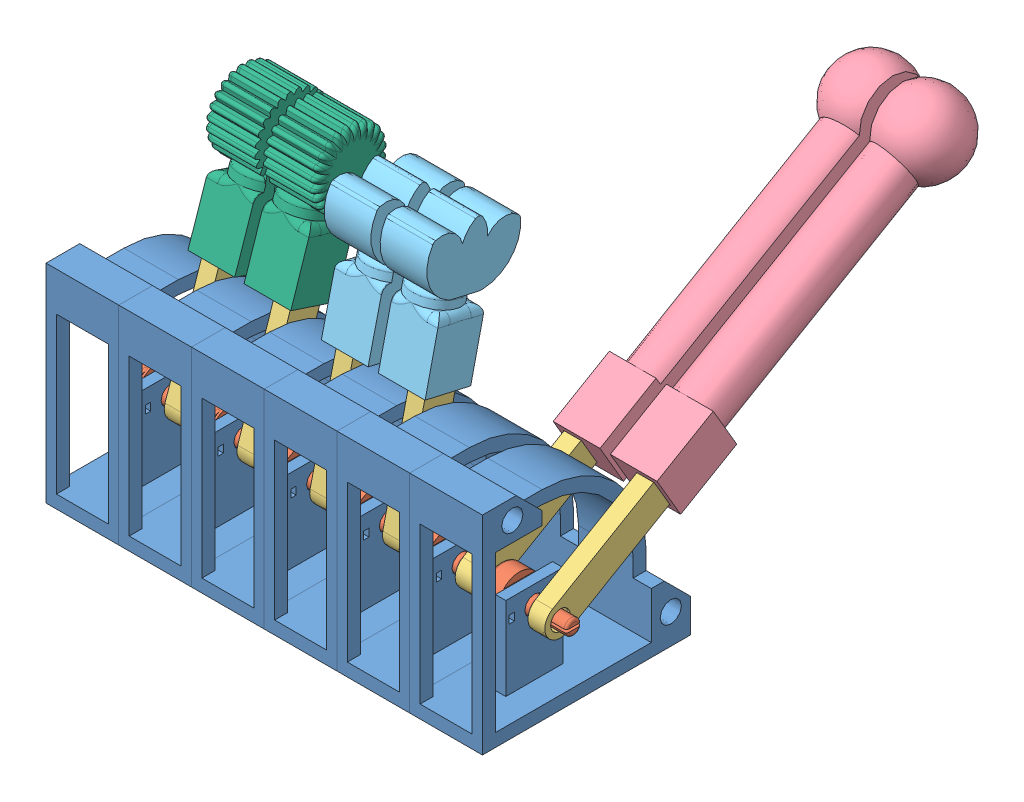
SolidWorks assembly throttle_quadrant_module_v2, configuration По умолчанию. Lengths in mm.
Overall size (176 136.41 197.26).
24 component instances, 6 part files, 57 mates.
Components (placement in the parent):
- throttle_quadrant_axis_module_throttle_quadrant01a-1: throttle_quadrant_axis_module_throttle_quadrant01a [По умолчанию] at origin size (28 80 80)
- 16K1-B10K-1: 16K1-B10K [По умолчанию] at (5.1 0 0) x (0 -1 0) z (0 0 1) size (20 28.16 16.3)
- throttle_quadrant_axis_module_slider_throttle_quadrant02a-1: throttle_quadrant_axis_module_slider_throttle_quadrant02a [По умолчанию] at (28 0 0) x (0 0.222506 0.974931) z (0 -0.974931 0.222506) size (12 6.5 71)
- throttle_quadrant_axis_module_throttle_quadrant01a-2: throttle_quadrant_axis_module_throttle_quadrant01a [По умолчанию] at (28 0 0) size (28 80 80)
- 16K1-B10K-2: 16K1-B10K [По умолчанию] at (33.1 0 0) x (0 -1 0) z (0 0 1) size (20 28.16 16.3)
- throttle_quadrant_axis_module_throttle_quadrant01a-4: throttle_quadrant_axis_module_throttle_quadrant01a [По умолчанию] at (56 0 0) size (28 80 80)
- throttle_quadrant_axis_module_slider_throttle_quadrant02a-2: throttle_quadrant_axis_module_slider_throttle_quadrant02a [По умолчанию] at (56 0 0) x (0 0.863825 0.503792) z (0 -0.503792 0.863825) size (12 6.5 71)
- throttle_quadrant_axis_module_slider_throttle_quadrant02a-3: throttle_quadrant_axis_module_slider_throttle_quadrant02a [По умолчанию] at (84 0 0) x (0 0.863572 0.504225) z (0 -0.504225 0.863572) size (12 6.5 71)
- 16K1-B10K-3: 16K1-B10K [По умолчанию] at (61.1 0 0) x (0 -1 0) z (0 0 1) size (20 28.16 16.3)
- mi8_throttle-1: mi8_throttle [По умолчанию] at (69 29.1657 -49.5546) x (1 0 0) z (0 0.863572 0.504225) size (23.51 140 30)
- mi8_throttle-2: mi8_throttle [По умолчанию] at (65 29.1408 -49.5692) x (-1 0 0) z (0 -0.863825 -0.503792) size (23.51 140 30)
- throttle_quadrant_axis_module_throttle_quadrant01a-5: throttle_quadrant_axis_module_throttle_quadrant01a [По умолчанию] at (-28 0 0) size (28 80 80)
- 16K1-B10K-4: 16K1-B10K [По умолчанию] at (-22.9 0 0) x (0 -1 0) z (0 0 1) size (20 28.16 16.3)
- throttle_quadrant_axis_module_slider_throttle_quadrant02a-4: throttle_quadrant_axis_module_slider_throttle_quadrant02a [По умолчанию] x (0 0.23184 0.972754) z (0 -0.972754 0.23184) size (12 6.5 71)
- prop_knob-1: prop_knob [По умолчанию] at (8.5 55.9797 -13.1363) x (-1 0 0) z (0 -0.23184 -0.972754) size (18 54.43 36.33)
- prop_knob-2: prop_knob [По умолчанию] at (12.5 56.0141 -12.9891) x (1 0 0) z (0 0.222506 0.974931) size (18 54.43 36.33)
- throttle_quadrant_axis_module_throttle_quadrant01a-6: throttle_quadrant_axis_module_throttle_quadrant01a [По умолчанию] at (-84 0 0) size (28 80 80)
- throttle_quadrant_axis_module_throttle_quadrant01a-7: throttle_quadrant_axis_module_throttle_quadrant01a [По умолчанию] at (-56 0 0) size (28 80 80)
- 16K1-B10K-5: 16K1-B10K [По умолчанию] at (-78.9 0 0) x (0 -0.381849 0.924225) z (0 0.924225 0.381849) size (20 28.16 16.3)
- 16K1-B10K-6: 16K1-B10K [По умолчанию] at (-50.9 0 0) x (0 -0.381849 0.924225) z (0 0.924225 0.381849) size (20 28.16 16.3)
- throttle_quadrant_axis_module_slider_throttle_quadrant02a-5: throttle_quadrant_axis_module_slider_throttle_quadrant02a [По умолчанию] at (-56 0 0) x (0 0.3217 0.946842) z (0 -0.946842 0.3217) size (12 6.5 71)
- throttle_quadrant_axis_module_slider_throttle_quadrant02a-6: throttle_quadrant_axis_module_slider_throttle_quadrant02a [По умолчанию] at (-28 0 0) x (0 0.31364 0.949542) z (0 -0.949542 0.31364) size (12 6.5 71)
- mix_knob-1: mix_knob [По умолчанию] at (-47.5 54.3791 -18.6871) x (-1 0 0) z (0 -0.3217 -0.946842) size (20 56.24 28.48)
- mix_knob-2: mix_knob [По умолчанию] at (-43.5 54.5359 -18.2242) x (1 0 0) z (0 0.31364 0.949542) size (20 56.24 28.48)
Mates (geometry in assembly coordinates):
- Concentric1: concentric anti-aligned: cylinder of throttle_quadrant_axis_module_throttle_quadrant01a-1 through (14 0 0) axis (1 0 0) radius 3.7; cylinder of 16K1-B10K-1 through (20.4 0 0) axis (-1 0 0) radius 3.35
- Coincident1: coincident anti-aligned: plane of throttle_quadrant_axis_module_throttle_quadrant01a-1 through (14 0 0) normal (-1 0 0); plane of 16K1-B10K-1 through (14 0 0) normal (1 0 0)
- Concentric2: concentric anti-aligned: cylinder of 16K1-B10K-1 through (33.2 0 0) axis (-1 0 0) radius 2.9; cylinder of throttle_quadrant_axis_module_slider_throttle_quadrant02a-1 through (21.5 0 0) axis (1 0 0) radius 3.75
- Distance2: distance = 0.5 mm anti-aligned: plane of throttle_quadrant_axis_module_slider_throttle_quadrant02a-1 through (21.5 0 0) normal (-1 0 0); plane of throttle_quadrant_axis_module_throttle_quadrant01a-1 through (21 0 0) normal (1 0 0)
- Concentric3: concentric aligned: cylinder of throttle_quadrant_axis_module_throttle_quadrant01a-1 through (0 42.5 18.5) axis (1 0 0) radius 4.1; cylinder of throttle_quadrant_axis_module_throttle_quadrant01a-2 through (28 42.5 18.5) axis (1 0 0) radius 4.1
- Concentric4: concentric aligned: cylinder of throttle_quadrant_axis_module_throttle_quadrant01a-1 through (0 -18.5 -42.5) axis (1 0 0) radius 4.1; cylinder of throttle_quadrant_axis_module_throttle_quadrant01a-2 through (28 -18.5 -42.5) axis (1 0 0) radius 4.1
- Coincident5: coincident anti-aligned: plane of throttle_quadrant_axis_module_throttle_quadrant01a-1 through (28 0 0) normal (1 0 0); plane of throttle_quadrant_axis_module_throttle_quadrant01a-2 through (28 0 0) normal (-1 0 0)
- Concentric5: concentric anti-aligned: cylinder of throttle_quadrant_axis_module_throttle_quadrant01a-2 through (42 0 0) axis (1 0 0) radius 3.7; cylinder of 16K1-B10K-2 through (48.4 0 0) axis (-1 0 0) radius 3.35
- Coincident6: coincident anti-aligned: plane of throttle_quadrant_axis_module_throttle_quadrant01a-2 through (42 0 0) normal (-1 0 0); plane of 16K1-B10K-2 through (42 0 0) normal (1 0 0)
- Concentric8: concentric aligned: cylinder of throttle_quadrant_axis_module_throttle_quadrant01a-2 through (28 42.5 18.5) axis (1 0 0) radius 4.1; cylinder of throttle_quadrant_axis_module_throttle_quadrant01a-4 through (56 42.5 18.5) axis (1 0 0) radius 4.1
- Concentric9: concentric aligned: cylinder of throttle_quadrant_axis_module_throttle_quadrant01a-2 through (28 -18.5 -42.5) axis (1 0 0) radius 4.1; cylinder of throttle_quadrant_axis_module_throttle_quadrant01a-4 through (56 -18.5 -42.5) axis (1 0 0) radius 4.1
- Coincident8: coincident anti-aligned: plane of throttle_quadrant_axis_module_throttle_quadrant01a-2 through (56 0 0) normal (1 0 0); plane of throttle_quadrant_axis_module_throttle_quadrant01a-4 through (56 0 0) normal (-1 0 0)
- Concentric10: concentric anti-aligned: cylinder of 16K1-B10K-2 through (61.2 0 0) axis (-1 0 0) radius 2.9; cylinder of throttle_quadrant_axis_module_slider_throttle_quadrant02a-2 through (49.5 0 0) axis (1 0 0) radius 3.75
- Concentric11: concentric anti-aligned: cylinder of throttle_quadrant_axis_module_throttle_quadrant01a-4 through (70 0 0) axis (1 0 0) radius 3.7; cylinder of 16K1-B10K-3 through (76.4 0 0) axis (-1 0 0) radius 3.35
- Coincident10: coincident anti-aligned: plane of throttle_quadrant_axis_module_throttle_quadrant01a-4 through (70 0 0) normal (-1 0 0); plane of 16K1-B10K-3 through (70 0 0) normal (1 0 0)
- Concentric12: concentric anti-aligned: cylinder of throttle_quadrant_axis_module_slider_throttle_quadrant02a-3 through (77.5 0 0) axis (1 0 0) radius 3.75; cylinder of 16K1-B10K-3 through (89.2 0 0) axis (-1 0 0) radius 2.9
- Distance4: distance = 0.5 mm anti-aligned: plane of throttle_quadrant_axis_module_slider_throttle_quadrant02a-2 through (49.5 0 0) normal (-1 0 0); plane of throttle_quadrant_axis_module_throttle_quadrant01a-2 through (49 0 0) normal (1 0 0)
- Distance5: distance = 0.5 mm anti-aligned: plane of throttle_quadrant_axis_module_slider_throttle_quadrant02a-3 through (77.5 0 0) normal (-1 0 0); plane of throttle_quadrant_axis_module_throttle_quadrant01a-4 through (77 0 0) normal (1 0 0)
- Coincident13: coincident anti-aligned: plane of throttle_quadrant_axis_module_slider_throttle_quadrant02a-3 through (77.5 0 0) normal (-1 0 0); plane of mi8_throttle-1 through (77.5 27.5932 -59.1575) normal (1 0 0)
- Coincident14: coincident anti-aligned: plane of throttle_quadrant_axis_module_slider_throttle_quadrant02a-3 through (77.5 27.5932 -59.1575) normal (0 0.504225 -0.863572); plane of mi8_throttle-1 through (69 32.9474 -56.0313) normal (0 -0.504225 0.863572)
- Coincident15: coincident anti-aligned: plane of throttle_quadrant_axis_module_slider_throttle_quadrant02a-3 through (77.5 -5.1814 -3.0254) normal (0 -0.863572 -0.504225); plane of mi8_throttle-1 through (77.5 27.5932 -59.1575) normal (0 0.863572 0.504225)
- Coincident16: coincident anti-aligned: plane of throttle_quadrant_axis_module_slider_throttle_quadrant02a-2 through (49.5 0 0) normal (-1 0 0); plane of mi8_throttle-2 through (49.5 38.275 -52.9243) normal (1 0 0)
- Coincident17: coincident anti-aligned: plane of throttle_quadrant_axis_module_slider_throttle_quadrant02a-2 through (49.5 27.5636 -59.1714) normal (0 0.503792 -0.863825); plane of mi8_throttle-2 through (65 32.9193 -56.0479) normal (0 -0.503792 0.863825)
- Coincident18: coincident anti-aligned: plane of throttle_quadrant_axis_module_slider_throttle_quadrant02a-2 through (49.5 -5.1829 -3.0228) normal (0 -0.863825 -0.503792); plane of mi8_throttle-2 through (56.5 27.5636 -59.1714) normal (0 0.863825 0.503792)
- Concentric14: concentric aligned: cylinder of throttle_quadrant_axis_module_throttle_quadrant01a-1 through (0 42.5 18.5) axis (1 0 0) radius 4.1; cylinder of throttle_quadrant_axis_module_throttle_quadrant01a-5 through (-28 42.5 18.5) axis (1 0 0) radius 4.1
- Concentric15: concentric aligned: cylinder of throttle_quadrant_axis_module_throttle_quadrant01a-1 through (0 -18.5 -42.5) axis (1 0 0) radius 4.1; cylinder of throttle_quadrant_axis_module_throttle_quadrant01a-5 through (-28 -18.5 -42.5) axis (1 0 0) radius 4.1
- Coincident19: coincident anti-aligned: plane of throttle_quadrant_axis_module_throttle_quadrant01a-1 through (0 0 0) normal (-1 0 0); plane of throttle_quadrant_axis_module_throttle_quadrant01a-5 through (0 0 0) normal (1 0 0)
- Concentric16: concentric anti-aligned: cylinder of throttle_quadrant_axis_module_throttle_quadrant01a-5 through (-14 0 0) axis (1 0 0) radius 3.7; cylinder of 16K1-B10K-4 through (-7.6 0 0) axis (-1 0 0) radius 3.35
- Coincident20: coincident anti-aligned: plane of throttle_quadrant_axis_module_throttle_quadrant01a-5 through (-14 0 0) normal (-1 0 0); plane of 16K1-B10K-4 through (-14 0 0) normal (1 0 0)
- Concentric17: concentric anti-aligned: cylinder of 16K1-B10K-4 through (5.2 0 0) axis (-1 0 0) radius 2.9; cylinder of throttle_quadrant_axis_module_slider_throttle_quadrant02a-4 through (-6.5 0 0) axis (1 0 0) radius 3.75
- Distance6: distance = 0.5 mm anti-aligned: plane of throttle_quadrant_axis_module_slider_throttle_quadrant02a-4 through (-6.5 0 0) normal (-1 0 0); plane of throttle_quadrant_axis_module_throttle_quadrant01a-5 through (-7 0 0) normal (1 0 0)
- Coincident22: coincident anti-aligned: plane of throttle_quadrant_axis_module_slider_throttle_quadrant02a-1; plane of prop_knob-2
- Coincident23: coincident anti-aligned: plane of throttle_quadrant_axis_module_slider_throttle_quadrant02a-1; plane of prop_knob-2
- Coincident24: coincident anti-aligned: plane of throttle_quadrant_axis_module_slider_throttle_quadrant02a-1 through (28 0 0) normal (1 0 0); plane of prop_knob-2 through (28 61.9465 -20.7024) normal (-1 0 0)
- Coincident25: coincident anti-aligned: plane of throttle_quadrant_axis_module_slider_throttle_quadrant02a-4 through (-6.5 61.838 -20.9061) normal (0 0.972754 -0.23184); plane of prop_knob-1 through (8.5 63.2754 -14.8751) normal (0 -0.972754 0.23184)
- Coincident32: coincident anti-aligned: plane of throttle_quadrant_axis_module_slider_throttle_quadrant02a-4 through (0 0 0) normal (1 0 0); plane of prop_knob-1 through (0 64.7128 -8.844) normal (-1 0 0)
- Coincident33: coincident anti-aligned: plane of throttle_quadrant_axis_module_slider_throttle_quadrant02a-4 through (-6.5 -1.391 -5.8365) normal (0 -0.23184 -0.972754); plane of prop_knob-1 through (0 61.838 -20.9061) normal (0 0.23184 0.972754)
- Coincident38: coincident anti-aligned: plane of throttle_quadrant_axis_module_throttle_quadrant01a-6 through (-56 0 0) normal (1 0 0); plane of throttle_quadrant_axis_module_throttle_quadrant01a-7 through (-56 0 0) normal (-1 0 0)
- Concentric18: concentric aligned: cylinder of throttle_quadrant_axis_module_throttle_quadrant01a-6 through (-84 42.5 18.5) axis (1 0 0) radius 4.1; cylinder of throttle_quadrant_axis_module_throttle_quadrant01a-7 through (-56 42.5 18.5) axis (1 0 0) radius 4.1
- Concentric19: concentric aligned: cylinder of throttle_quadrant_axis_module_throttle_quadrant01a-6 through (-84 -18.5 -42.5) axis (1 0 0) radius 4.1; cylinder of throttle_quadrant_axis_module_throttle_quadrant01a-7 through (-56 -18.5 -42.5) axis (1 0 0) radius 4.1
- Concentric20: concentric anti-aligned: cylinder of throttle_quadrant_axis_module_throttle_quadrant01a-7 through (-42 0 0) axis (1 0 0) radius 3.7; cylinder of 16K1-B10K-6 through (-35.6 0 0) axis (-1 0 0) radius 3.35
- Coincident39: coincident anti-aligned: plane of throttle_quadrant_axis_module_throttle_quadrant01a-7 through (-42 0 0) normal (-1 0 0); plane of 16K1-B10K-6 through (-42 0 0) normal (1 0 0)
- Concentric21: concentric anti-aligned: cylinder of throttle_quadrant_axis_module_throttle_quadrant01a-6 through (-70 0 0) axis (1 0 0) radius 3.7; cylinder of 16K1-B10K-5 through (-63.6 0 0) axis (-1 0 0) radius 3.35
- Coincident40: coincident anti-aligned: plane of throttle_quadrant_axis_module_throttle_quadrant01a-6 through (-70 0 0) normal (-1 0 0); plane of 16K1-B10K-5 through (-70 0 0) normal (1 0 0)
- Concentric22: concentric anti-aligned: cylinder of 16K1-B10K-6 through (-22.8 0 0) axis (-1 0 0) radius 2.9; cylinder of throttle_quadrant_axis_module_slider_throttle_quadrant02a-6 through (-34.5 0 0) axis (1 0 0) radius 3.75
- Distance7: distance = 0.5 mm anti-aligned: plane of throttle_quadrant_axis_module_slider_throttle_quadrant02a-6 through (-34.5 0 0) normal (-1 0 0); plane of throttle_quadrant_axis_module_throttle_quadrant01a-7 through (-35 0 0) normal (1 0 0)
- Concentric23: concentric anti-aligned: cylinder of 16K1-B10K-5 through (-50.8 0 0) axis (-1 0 0) radius 2.9; cylinder of throttle_quadrant_axis_module_slider_throttle_quadrant02a-5 through (-62.5 0 0) axis (1 0 0) radius 3.75
- Distance8: distance = 0.5 mm anti-aligned: plane of throttle_quadrant_axis_module_slider_throttle_quadrant02a-5 through (-62.5 0 0) normal (-1 0 0); plane of throttle_quadrant_axis_module_throttle_quadrant01a-6 through (-63 0 0) normal (1 0 0)
- Coincident43: coincident anti-aligned: plane of throttle_quadrant_axis_module_slider_throttle_quadrant02a-6 through (-34.5 59.8384 -26.0839) normal (0 0.949542 -0.31364); plane of mix_knob-2 through (-43.5 61.6575 -20.5765) normal (0 -0.949542 0.31364)
- Coincident44: coincident anti-aligned: plane of throttle_quadrant_axis_module_slider_throttle_quadrant02a-6 through (-28 0 0) normal (1 0 0); plane of mix_knob-2 through (-28 59.7129 -26.4637) normal (-1 0 0)
- Coincident45: coincident anti-aligned: plane of throttle_quadrant_axis_module_slider_throttle_quadrant02a-6 through (-34.5 63.6021 -14.6894) normal (0 0.31364 0.949542); plane of mix_knob-2 through (-35 63.6021 -14.6894) normal (0 -0.31364 -0.949542)
- Coincident46: coincident anti-aligned: plane of throttle_quadrant_axis_module_slider_throttle_quadrant02a-5 through (-62.5 59.6145 -26.5916) normal (0 0.946842 -0.3217); plane of mix_knob-1 through (-47.5 61.4804 -21.0999) normal (0 -0.946842 0.3217)
- Coincident47: coincident anti-aligned: plane of throttle_quadrant_axis_module_slider_throttle_quadrant02a-5 through (-56 0 0) normal (1 0 0); plane of mix_knob-1 through (-56 63.4749 -15.2295) normal (-1 0 0)
- Coincident48: coincident anti-aligned: plane of throttle_quadrant_axis_module_slider_throttle_quadrant02a-5 through (-62.5 63.4749 -15.2295) normal (0 0.3217 0.946842); plane of mix_knob-1 through (-56 63.4749 -15.2295) normal (0 -0.3217 -0.946842)
- Concentric26: concentric aligned: cylinder of throttle_quadrant_axis_module_throttle_quadrant01a-5 through (-28 42.5 18.5) axis (1 0 0) radius 4.1; cylinder of throttle_quadrant_axis_module_throttle_quadrant01a-7 through (-56 42.5 18.5) axis (1 0 0) radius 4.1
- Concentric27: concentric aligned: cylinder of throttle_quadrant_axis_module_throttle_quadrant01a-5 through (-28 -18.5 -42.5) axis (1 0 0) radius 4.1; cylinder of throttle_quadrant_axis_module_throttle_quadrant01a-6 through (-84 -18.5 -42.5) axis (1 0 0) radius 4.1
- Coincident53: coincident anti-aligned: plane of throttle_quadrant_axis_module_throttle_quadrant01a-5 through (-28 0 0) normal (-1 0 0); plane of throttle_quadrant_axis_module_throttle_quadrant01a-7 through (-28 0 0) normal (1 0 0)
